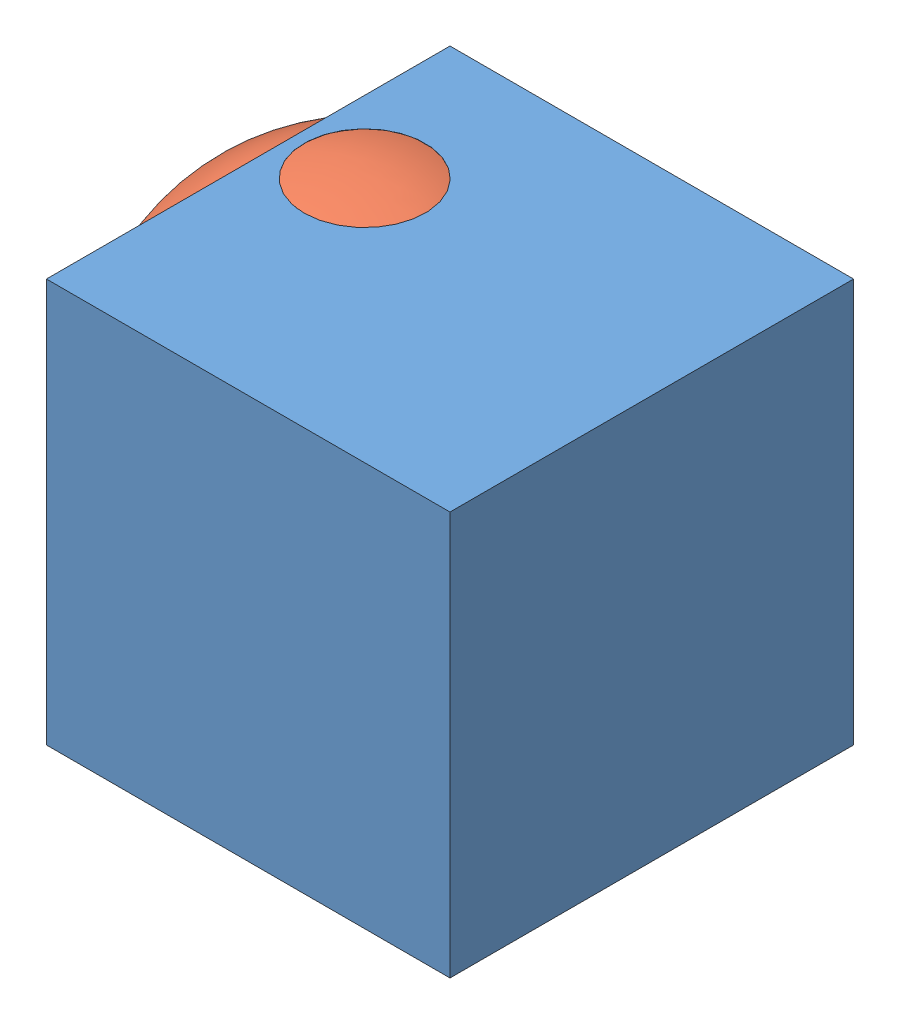
SolidWorks assembly test assembelly, configuration Default. Lengths in mm.
Overall size (40.85 36.59 32.31).
2 component instances, 2 part files, 1 mates.
Components (placement in the parent):
- PDM test-1: PDM test [Default] at origin size (25.4 25.4 25.4)
- ball-1: ball [Default] at (4.5205 13.285 9.8911) x (0.43728 0.899206 -0.014692) z (0.280785 -0.120988 0.952114) size (25.4 25.4 25.4)
Mates (geometry in assembly coordinates):
- Coincident1: coincident: circle of PDM test-1; sphere of ball-1
